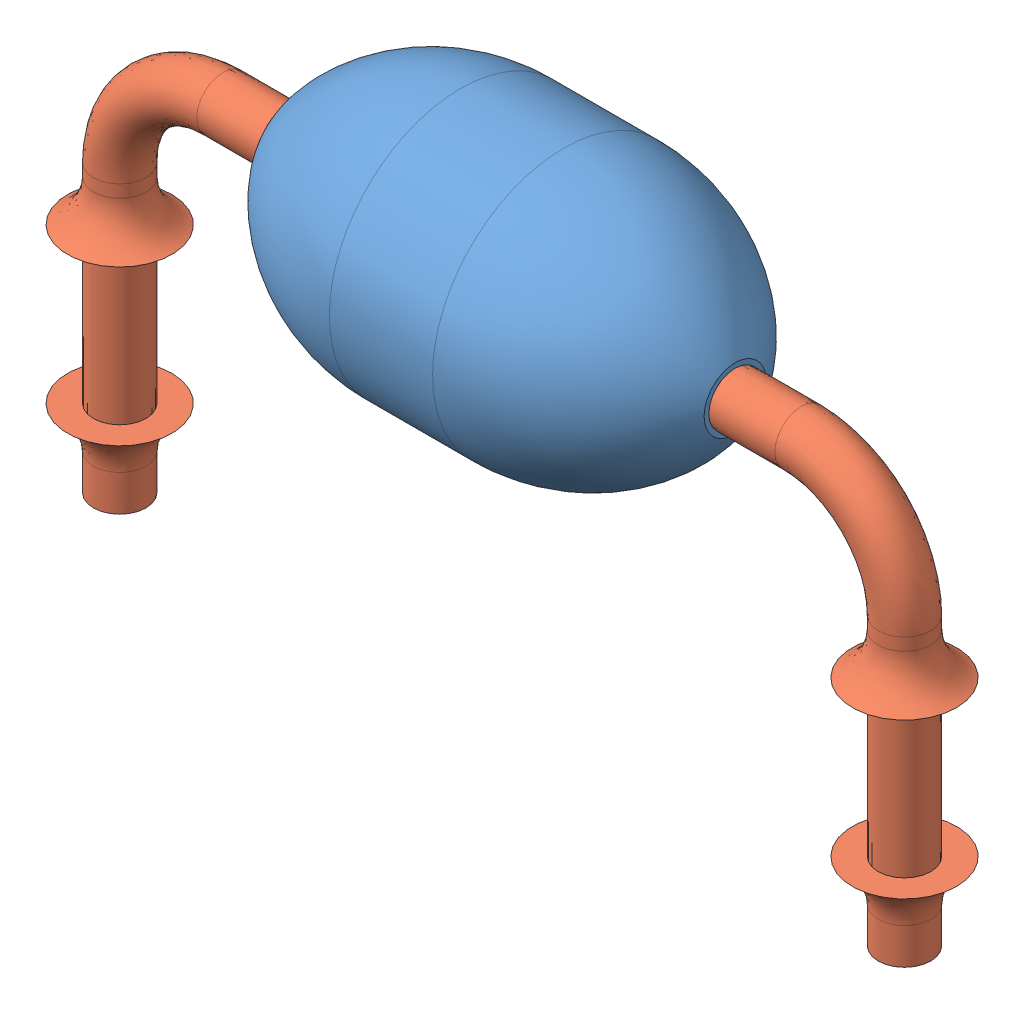
SolidWorks assembly KMET C410C104M5U5CA-TR, configuration Default. Lengths in mm.
Overall size (8.61 5.04 2.54).
2 component instances, 2 part files, 3 mates.
Components (placement in the parent):
- KMET C410C104M5U5CA-TR_2-1: KMET C410C104M5U5CA-TR_2 [Default] at (0.0435 0.0314 -0.0443) size (4.32 2.54 2.54)
- KMET C410C104M5U5CA-TR_1-1: KMET C410C104M5U5CA-TR_1 [Default] at (-3.7565 -1.7386 -0.0443) size (8.61 4.03 1.01)
Mates (geometry in assembly coordinates):
- Concentric1: concentric aligned: cylinder of KMET C410C104M5U5CA-TR_2-1 through (-2.1165 0.0314 -0.0443) axis (-1 0 0) radius 0.15; cylinder of KMET C410C104M5U5CA-TR_1-1 through (2.2035 0.0314 -0.0443) axis (-1 0 0) radius 0.2
- Coincident1: coincident anti-aligned: plane of KMET C410C104M5U5CA-TR_2-1 through (-2.1165 0.1814 -0.0443) normal (-1 0 0); plane of KMET C410C104M5U5CA-TR_1-1 through (-2.1165 0.0314 -0.0443) normal (1 0 0)
- PLANE1: unknown = 10 mm: plane of KMET C410C104M5U5CA-TR_2-1 through (0.0435 0.0314 -0.0443) normal (0 0 1)
